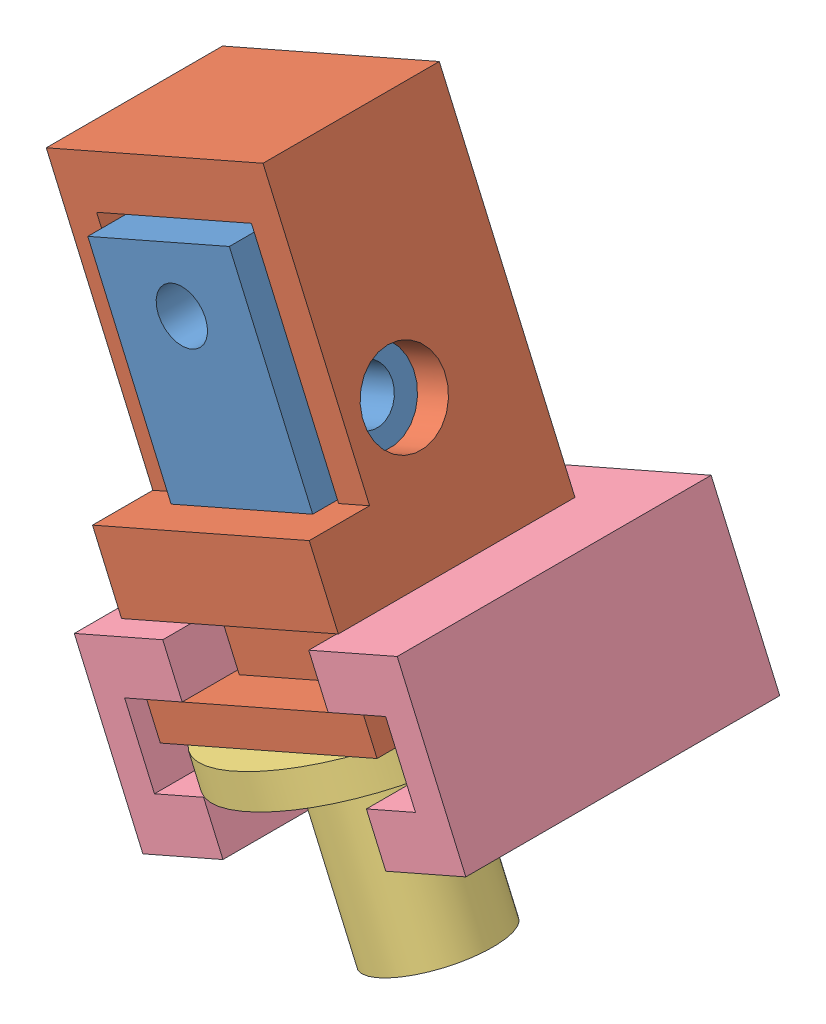
SolidWorks assembly 3mL_Syringe_Plunger_Attachment, configuration Default. Lengths in mm.
Overall size (25.71 35.61 18.56).
4 component instances, 4 part files, 8 mates.
Components (placement in the parent):
- Attachment_Blocks_585400_a-1: Attachment_Blocks_585400_a [Default] at (15.8825 -25.6254 7.6874) x (0.915939 0.401317 0) z (0 0 1) size (8.13 10.92 8.13)
- Part1^3mL_Syringe_Plunger_Attachment-1: Part1^3mL_Syringe_Plunger_Attachment [Default] at (-20.7281 -41.6663 11.683) x (0 0 1) z (0.401317 -0.915939 0) size (14.3 13.46 22.86) (virtual)
- Plunger_Flange-1: Plunger_Flange [Default] at (19.4503 -33.7681 9.0336) x (0.401317 -0.915939 0) z (-0.026645 -0.011675 0.999577) size (10.03 13.46 13.46)
- Part2^3mL_Syringe_Plunger_Attachment-1: Part2^3mL_Syringe_Plunger_Attachment [Default] at (-17.8739 -48.1804 11.683) x (0 0 -1) z (-0.401317 0.915939 0) size (16.51 18.54 8.99) (virtual)
Mates (geometry in assembly coordinates):
- Concentric2: concentric aligned: circle of Plunger_Flange-1; circle of Part1^3mL_Syringe_Plunger_Attachment-1
- Parallel1: parallel anti-aligned: plane of Plunger_Flange-1 through (19.4503 -33.7681 9.0336) normal (-0.401317 0.915939 0); plane of Part1^3mL_Syringe_Plunger_Attachment-1 through (17.4116 -29.1151 9.0336) normal (0.401317 -0.915939 0)
- Coincident5: coincident anti-aligned: plane of Part1^3mL_Syringe_Plunger_Attachment-1 through (-17.1604 -49.809 11.683) normal (0.401317 -0.915939 0); plane of Plunger_Flange-1 through (19.4503 -33.7681 9.0336) normal (-0.401317 0.915939 0)
- Coincident6: coincident aligned: plane of Attachment_Blocks_585400_a-1 through (19.6049 -23.9945 3.6234) normal (0.401317 -0.915939 0); plane of Part1^3mL_Syringe_Plunger_Attachment-1 through (-20.7281 -41.6663 11.683) normal (0.401317 -0.915939 0)
- InPlace1: in place: plane of Part1^3mL_Syringe_Plunger_Attachment-1 through (-17.8739 -48.1804 11.683) normal (-0.401317 0.915939 0); plane of ? through (14.8316 -33.8506 0) normal (-0.401317 0.915939 0); moOrthogonalPlaneRef_w of Part1^3mL_Syringe_Plunger_Attachment-1 through (-17.8739 -48.1804 11.683) normal (-0.401317 0.915939 0); unknown of ?; plane of Part1^3mL_Syringe_Plunger_Attachment-1 through (-17.8739 -48.1804 11.683) normal (-0.401317 0.915939 0); unknown of ?; plane of Part1^3mL_Syringe_Plunger_Attachment-1 through (-17.8739 -48.1804 11.683) normal (-0.401317 0.915939 0); unknown of Part2^3mL_Syringe_Plunger_Attachment-1
- Coincident8: coincident aligned: plane of Part1^3mL_Syringe_Plunger_Attachment-1; plane of Part2^3mL_Syringe_Plunger_Attachment-1
- Coincident9: coincident aligned: moOrthogonalPlaneRef_w of Part1^3mL_Syringe_Plunger_Attachment-1 through (-17.8739 -48.1804 11.683) normal (-0.915939 -0.401317 0); plane of Part2^3mL_Syringe_Plunger_Attachment-1
- Coincident10: coincident anti-aligned: moOrthogonalPlaneRef_w of Part1^3mL_Syringe_Plunger_Attachment-1 through (-17.8739 -48.1804 11.683) normal (0 0 1); plane of Part2^3mL_Syringe_Plunger_Attachment-1
